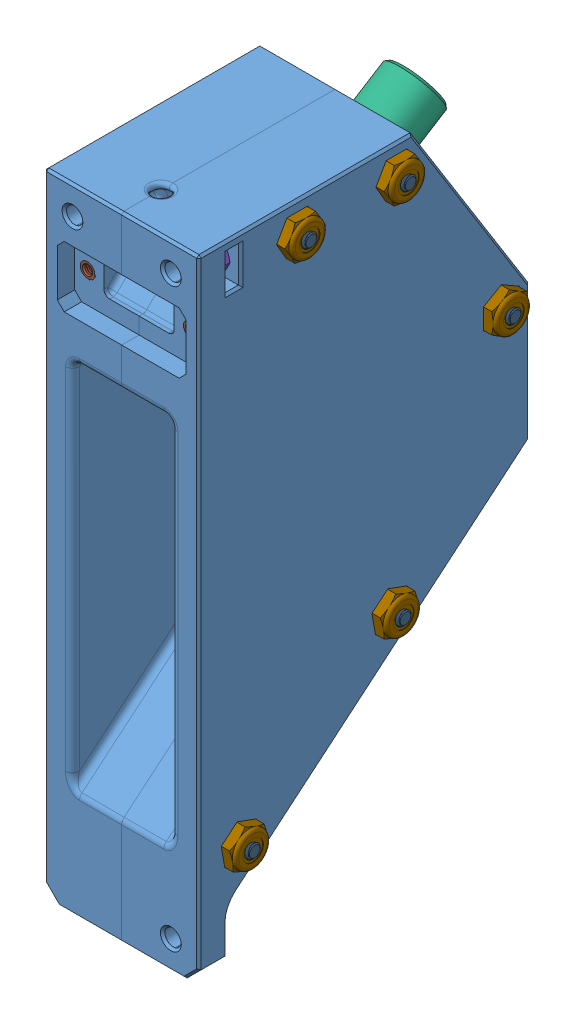
SolidWorks assembly Hook Lever Chassis, configuration Default. Lengths in mm.
Overall size (40.7 142.92 101.62).
25 component instances, 11 part files, 4 mates.
Components (placement in the parent):
- Hook Lever Chassis Body-1: Hook Lever Chassis Body [Default] at origin size (34.93 142.92 75.16)
- Hook Lever .25 Shaft -1: Hook Lever .25 Shaft  [Default] at origin size (31.75 6.35 6.35)
- 93365A120_BRASS HEAT-SET INSERT FOR PLASTICS_4-40-1: 93365A120_BRASS HEAT-SET INSERT FOR PLASTICS_4-40 [93365A120] at (-11.1125 2.6229 -53.39) x (0 1 0) z (0 0 -1) size (4.37 3.82 4.37)
- 93365A120_BRASS HEAT-SET INSERT FOR PLASTICS_4-40-2: 93365A120_BRASS HEAT-SET INSERT FOR PLASTICS_4-40 [93365A120] at (-11.1125 24.8048 -63.6241) x (0 -1 0) z (0 0 1) size (4.37 3.82 4.37)
- 7779K52-1: 7779K52 [Default] at (-5.9575 13.7248 -58.4313) x (0 0.642788 -0.766044) z (1 0 0) size (37.8 27.88 10.31)
- 91249A115-1: 91249A115 [Default] at (-16.6775 2.6447 -53.2386) x (0 -0.642788 0.766044) z (1 0 0) size (23.09 11.07 22.41)
- 91249A115-2: 91249A115 [Default] at (-16.6775 24.8048 -63.6241) x (0 -0.642788 0.766044) z (1 0 0) size (23.09 11.07 22.41)
- 84835A14-1: 84835A14 [Default] at (0 68.5051 -51.909) x (1 0 0) z (0 0.848048 0.529919) size (17.48 34.82 17.48)
- 92141A029-1: 92141A029 [Default] at (-11.1887 50.8 -23.575) x (0 1 0) z (0 0 1) size (15.88 1.45 15.88)
- 92141A029-2: 92141A029 [Default] at (11.1887 50.8 -23.575) x (0 -1 0) z (0 0 1) size (15.88 1.45 15.88)
- 91841A007-1: 91841A007 [Default] at (11.1125 -50.8 -6.4691) x (1 0 0) z (0 1 0) size (9.17 3.79 9.17)
- 91841A007-3: 91841A007 [Default] at (11.1125 79.375 -7.7391) x (0 -1 0) z (1 0 0) size (9.17 3.79 9.17)
- 91841A007-4: 91841A007 [Default] at (-11.1125 79.375 -7.7391) x (0 -1 0) z (1 0 0) size (9.17 3.79 9.17)
- 91831A007-1: 91831A007 [Default] at (15.875 -33.7081 -9.4371) x (0 -0.939693 0.34202) z (0 0.34202 0.939693) size (7.94 4.49 9.17)
- 91831A007-2: 91831A007 [Default] at (15.875 -5.1362 -43.4878) x (0 -0.939693 0.34202) z (0 0.34202 0.939693) size (7.94 4.49 9.17)
- 91831A007-3: 91831A007 [Default] at (15.875 41.4731 -68.3396) x (0 -0.866025 0.5) z (0 0.5 0.866025) size (7.94 4.49 9.17)
- 91831A007-4: 91831A007 [Default] at (15.875 79.375 -44.6558) x (0 -1 0) z (0 0 1) size (7.94 4.49 9.17)
- 91831A007-5: 91831A007 [Default] at (15.875 79.375 -22.225) x (0 -1 0) z (0 0 1) size (7.94 4.49 9.17)
- 91249A164 - PHS, 6-32 X 1.50, STEEL, BLACK OXIDE-1: 91249A164 - PHS, 6-32 X 1.50, STEEL, BLACK OXIDE [91249A164] at (20.6375 41.4731 -68.3396) x (0 0 1) z (-1 0 0) size (6.86 6.86 40.7)
- 91249A164 - PHS, 6-32 X 1.50, STEEL, BLACK OXIDE-2: 91249A164 - PHS, 6-32 X 1.50, STEEL, BLACK OXIDE [91249A164] at (20.6375 -5.1362 -43.4878) x (0 0 1) z (-1 0 0) size (6.86 6.86 40.7)
- 91249A164 - PHS, 6-32 X 1.50, STEEL, BLACK OXIDE-3: 91249A164 - PHS, 6-32 X 1.50, STEEL, BLACK OXIDE [91249A164] at (20.6375 79.375 -44.6558) x (0 0 1) z (-1 0 0) size (6.86 6.86 40.7)
- 91249A164 - PHS, 6-32 X 1.50, STEEL, BLACK OXIDE-4: 91249A164 - PHS, 6-32 X 1.50, STEEL, BLACK OXIDE [91249A164] at (20.6375 -33.7081 -9.4371) x (0 0 1) z (-1 0 0) size (6.86 6.86 40.7)
- 91249A164 - PHS, 6-32 X 1.50, STEEL, BLACK OXIDE-5: 91249A164 - PHS, 6-32 X 1.50, STEEL, BLACK OXIDE [91249A164] at (20.6375 79.375 -22.225) x (0 0 1) z (-1 0 0) size (6.86 6.86 40.7)
- 93365A110_BRASS HEAT-SET INSERT FOR PLASTICS_2-56-1: 93365A110_BRASS HEAT-SET INSERT FOR PLASTICS_2-56 [Default] at (-11.6522 66.675 -3.937) x (1 0 0) z (0 -1 0) size (3.58 3.09 3.58)
- 93365A110_BRASS HEAT-SET INSERT FOR PLASTICS_2-56-2: 93365A110_BRASS HEAT-SET INSERT FOR PLASTICS_2-56 [Default] at (11.6523 66.675 -3.937) x (0.987351 0.158553 0) z (0.158553 -0.987351 0) size (3.58 3.09 3.58)
Mates (geometry in assembly coordinates):
- Concentric1: concentric aligned: cone of Hook Lever Chassis Body-1 through (-11.6522 66.675 -3.937) axis (0 0 -1); cone of 93365A110_BRASS HEAT-SET INSERT FOR PLASTICS_2-56-1 through (-11.6522 66.675 -5.047) axis (0 0 -1)
- Coincident1: coincident aligned: plane of Hook Lever Chassis Body-1 through (0 0 -3.937) normal (0 0 1); plane of 93365A110_BRASS HEAT-SET INSERT FOR PLASTICS_2-56-1 through (-13.4429 66.675 -3.937) normal (0 0 1)
- Concentric2: concentric aligned: cone of Hook Lever Chassis Body-1 through (11.6523 66.675 -3.937) axis (0 0 -1); cone of 93365A110_BRASS HEAT-SET INSERT FOR PLASTICS_2-56-2 through (11.6523 66.675 -5.047) axis (0 0 -1)
- Coincident2: coincident aligned: plane of Hook Lever Chassis Body-1 through (0 0 -3.937) normal (0 0 1); plane of 93365A110_BRASS HEAT-SET INSERT FOR PLASTICS_2-56-2 through (9.8842 66.3911 -3.937) normal (0 0 1)
